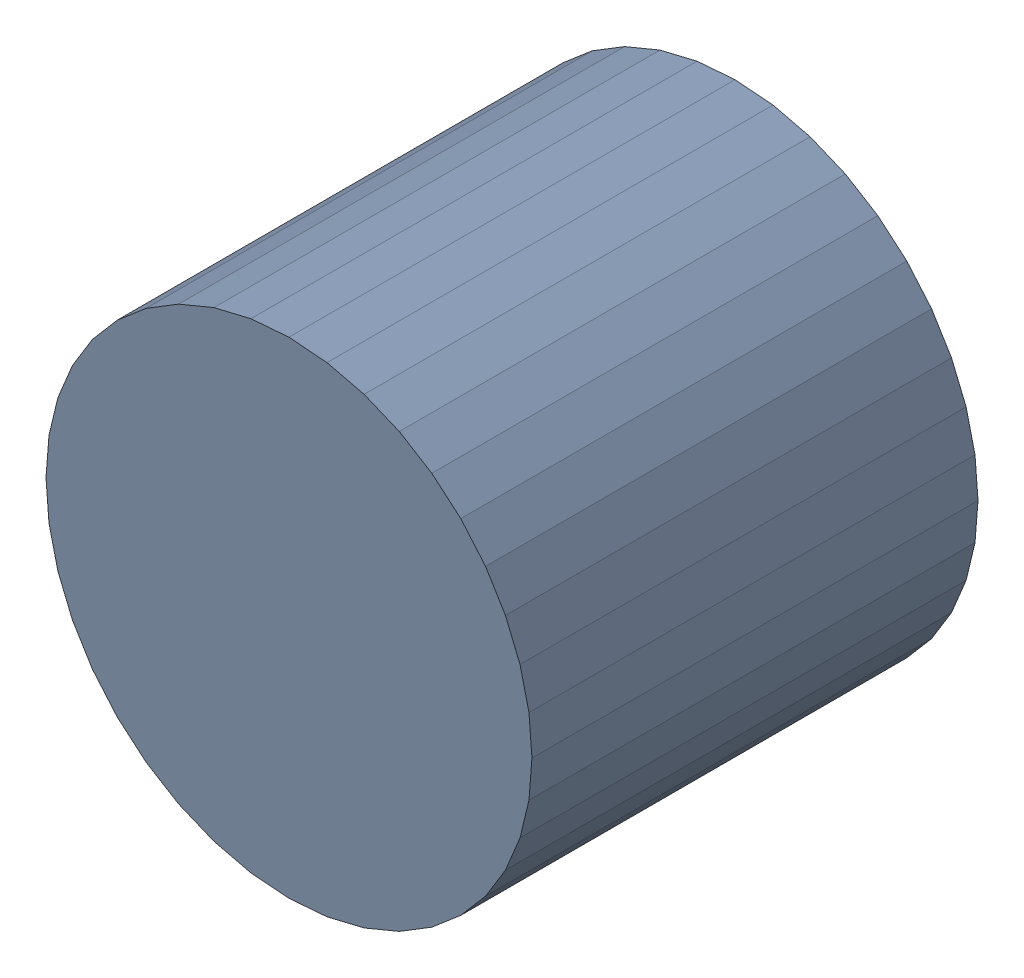
SolidWorks assembly CoutB1_1Kanaloa_v2.0.0_Power, configuration Default. Lengths in mm.
Overall size (6.32 6.32 5.8).
2 component instances, 1 part files, 0 mates.
Components (placement in the parent):
- 352892112-1: 352892112 [Default] at (134.875 45.3 0) size (6.32 6.32 5.8)
  - Extruded_11-1: Extruded_11 [Default] at origin size (6.32 6.32 5.8)
